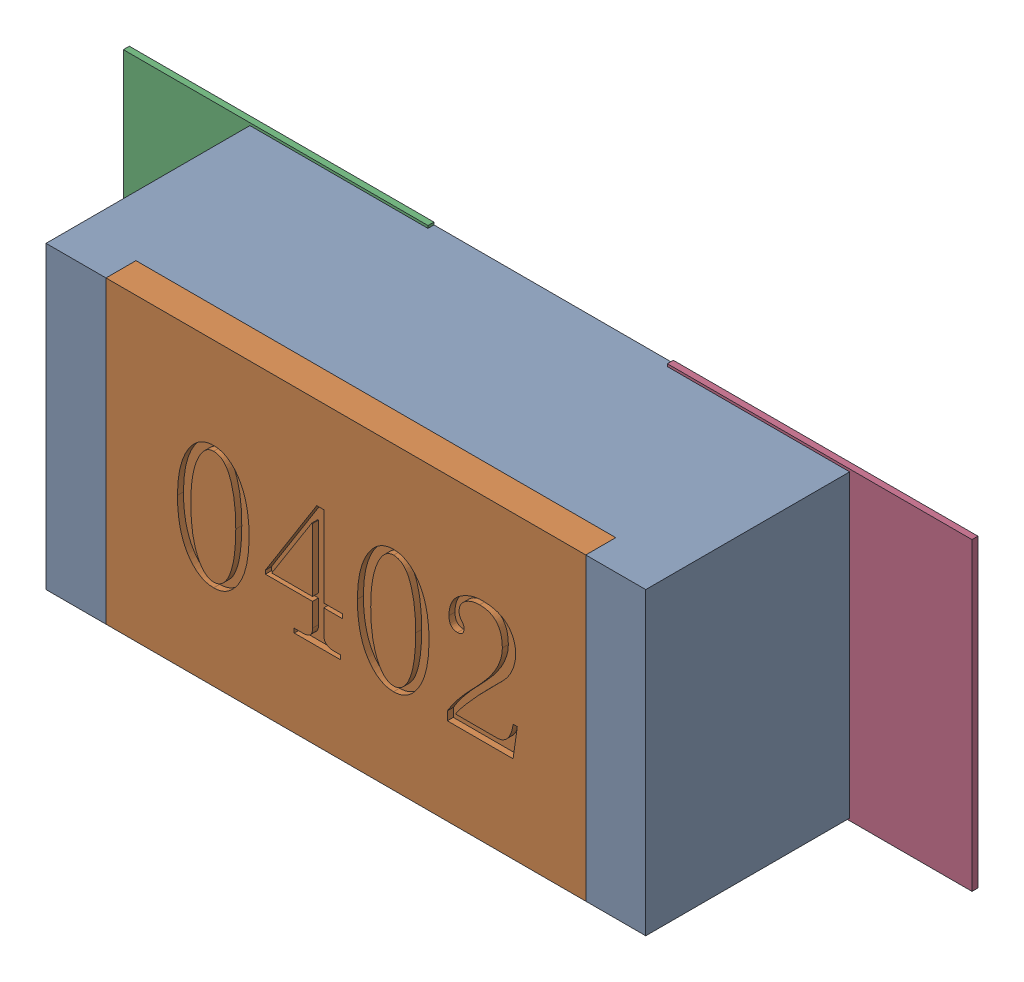
SolidWorks assembly R92, configuration Défaut. Lengths in mm.
Overall size (1.42 0.51 0.35).
5 component instances, 2 part files, 0 mates.
Components (placement in the parent):
- R0402-1: R0402 [Défaut] at (53.8734 -29.0323 0) x (1 0 0) z (0 0 1) size (1 0.5 0.35)
- 6504207776-1: 6504207776 [Défaut] at (53.4163 -29.0321 0) size (0.51 0.51 0.01)
  - Extruded-1: Extruded [Défaut] at origin size (0.51 0.51 0.01)
- 6504207776-2: 6504207776 [Défaut] at (54.3234 -29.0321 0) size (0.51 0.51 0.01)
  - Extruded-1: Extruded [Défaut] at origin size (0.51 0.51 0.01)
